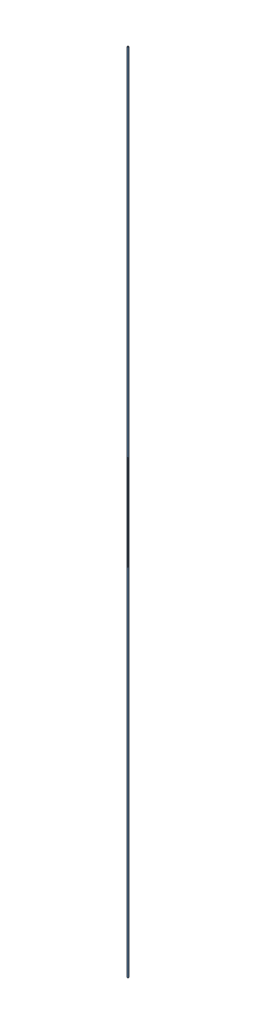
SolidWorks assembly 绳组合, configuration 默认. Lengths in mm.
Overall size (5 1430.5 5).
2 component instances, 1 part files, 1 mates.
Components (placement in the parent):
- 绳2-1: 绳2 [默认] at (-25.9358 -29.6231 70) size (4 800 4)
- 绳2-2: 绳2 [默认] at (-25.9358 600.878 70) x (-0.292934 0 0.956133) z (-0.956133 0 -0.292934) size (4 800 4)
Mates (geometry in assembly coordinates):
- 同心1: concentric aligned: circle of 绳2-1; circle of 绳2-2
